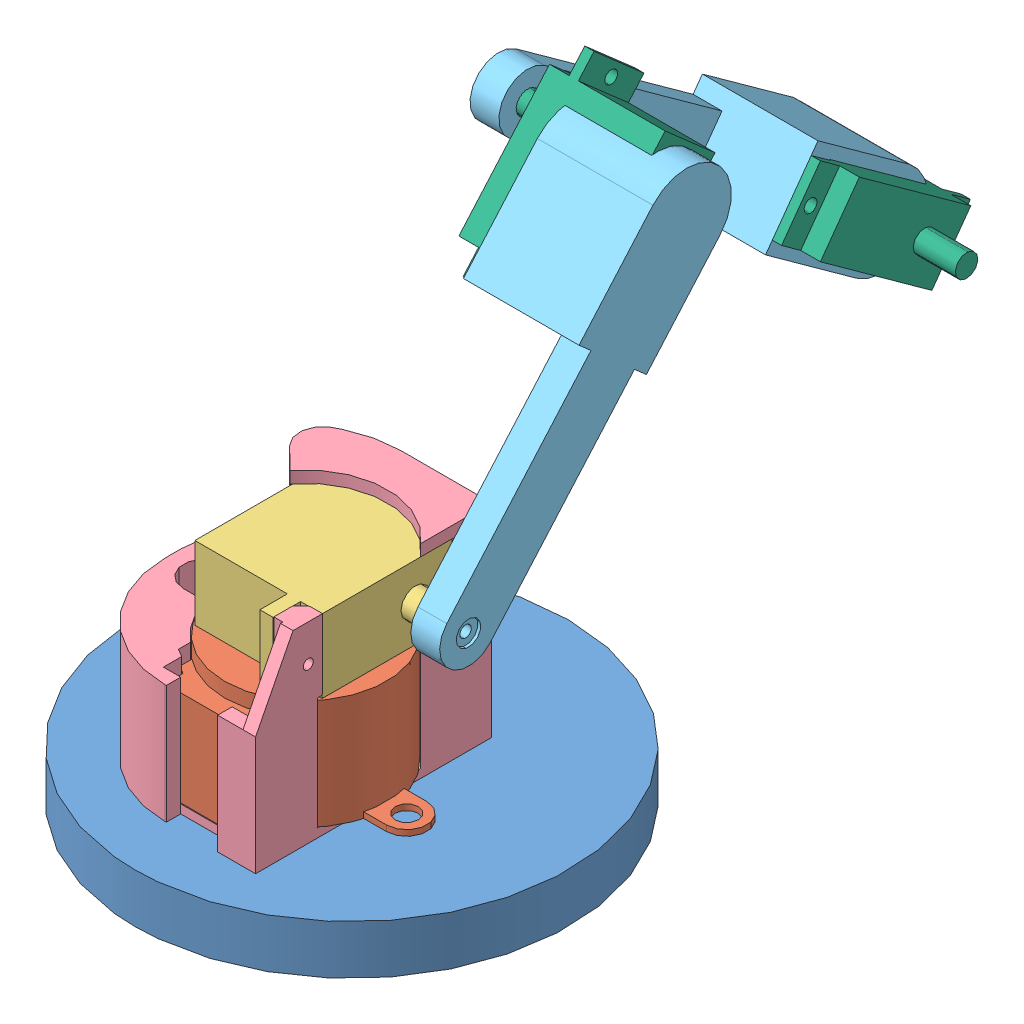
SolidWorks assembly MicroArm, configuration Default. Lengths in mm.
Overall size (75 92.99 138.21).
11 component instances, 6 part files, 7 mates.
Components (placement in the parent):
- Base-1: Base [Default] at origin size (75 8.5 75)
- Shoulder-1: Shoulder [Default] at (0 10 8) x (-1 0 0) z (0 0 -1) size (44.65 43.7 40.8)
  - StepperMotor-1: StepperMotor [Default] at origin size (42 29 31)
  - SG92rMicroServo-1: SG92rMicroServo [Alignment] at (11 25.35 3.1) x (0 0 1) z (-1 0 0) size (32 12.7 29.2)
  - BaseShoulder-1: BaseShoulder [Default] at origin size (34.65 35.2 40.8)
- Elbow-1: Elbow [Default] at (15.2 35.35 0) x (0 0.75199 -0.659174) z (1 0 0) size (74.85 15.5 32.3)
  - UpperArmLink-1: UpperArmLink [Default] at origin size (70 15.5 20)
  - SG90MicroServo-1: SG90MicroServo [Default] at (53.85 0 0) x (1 0 0) z (0 0 -1) size (32 11.5 27.3)
- Elbow-2: Elbow [SG90] at (-9.1 80.4694 -39.5505) x (0 -0.58555 -0.810636) z (-1 0 0) size (74.85 15.5 32.3)
  - UpperArmLink-1: UpperArmLink [SG90] at origin size (70 15.5 20)
  - SG90MicroServo-1: SG90MicroServo [Default] at (53.85 0 0) x (1 0 0) z (0 0 -1) size (32 11.5 27.3)
Mates (geometry in assembly coordinates):
- Concentric1: concentric aligned: cylinder of Base-1 through (0 6 0) axis (0 1 0) radius 2.625; cylinder of Shoulder-1/StepperMotor-1 through (0 6 0) axis (0 1 0) radius 2.5
- Coincident1: coincident anti-aligned: plane of Base-1 through (0 8.5 0) normal (0 1 0); plane of Shoulder-1/StepperMotor-1 through (0 8.5 0) normal (0 -1 0)
- Concentric2: concentric anti-aligned: circle of Shoulder-1/SG92rMicroServo-1; cylinder of Elbow-1/UpperArmLink-1 through (15.2 35.35 0) axis (1 0 0) radius 1
- Coincident2: coincident anti-aligned: plane of Shoulder-1/SG92rMicroServo-1 through (18.2 35.35 4.9) normal (1 0 0); plane of Elbow-1/UpperArmLink-1 through (18.2 35.35 0) normal (-1 0 0)
- Parallel1: parallel anti-aligned: plane of Base-1 through (1.525 0 -2.1366) normal (-1 0 0); plane of Shoulder-1/StepperMotor-1 through (1.5 0 -2) normal (1 0 0)
- Concentric3: concentric aligned: cylinder of Elbow-1/SG90MicroServo-1 through (-44.9154 80.4694 -39.5505) axis (1 0 0) radius 1.95; cylinder of Elbow-2/UpperArmLink-1 through (-12.1 80.4694 -39.5505) axis (1 0 0) radius 2.0125
- Coincident3: coincident anti-aligned: plane of Elbow-1/SG90MicroServo-1 through (-12.1 75.8447 -35.4965) normal (-1 0 0); plane of Elbow-2/UpperArmLink-1 through (-12.1 80.4694 -39.5505) normal (1 0 0)
